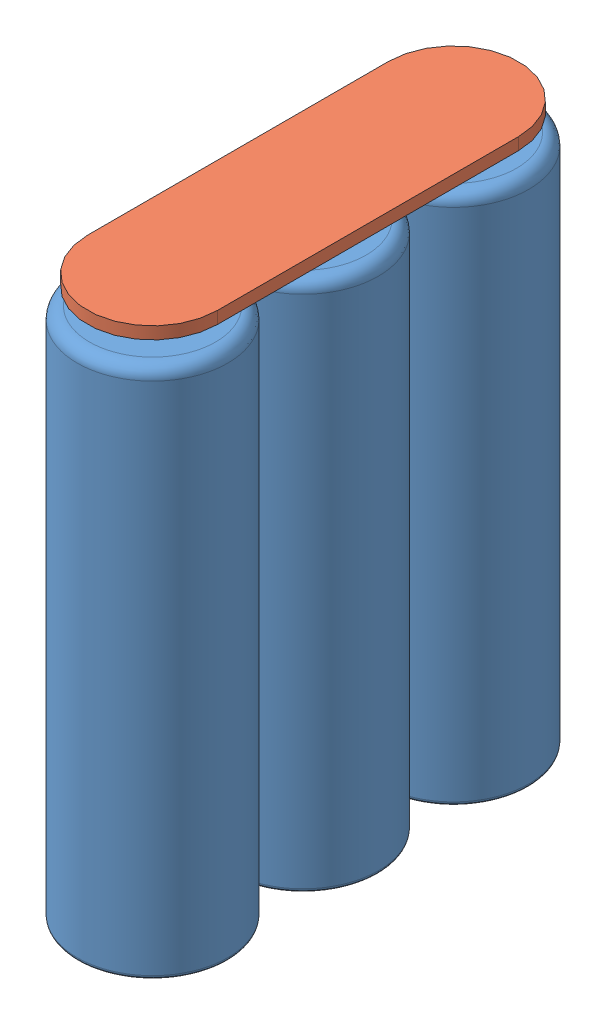
SolidWorks assembly battery_block, configuration По умолчанию. Lengths in mm.
Overall size (18.5 68.8 55.5).
4 component instances, 2 part files, 3 mates.
Components (placement in the parent):
- Sanjo NCR18650GA-1: Sanjo NCR18650GA [Standard] at origin size (18.5 65.3 18.5)
- Sanjo NCR18650GA-2: Sanjo NCR18650GA [Standard] at (0 0 18.5) size (18.5 65.3 18.5)
- Sanjo NCR18650GA-3: Sanjo NCR18650GA [Standard] at (0 0 37) size (18.5 65.3 18.5)
- balansir_pcb-1: balansir_pcb [По умолчанию] at (0 68.8 18.5) x (1 0 0) z (0 -1 0) size (16 53 1.5)
Mates (geometry in assembly coordinates):
- Concentric1: concentric anti-aligned: cylinder of Sanjo NCR18650GA-1 through (0 65.3 0) axis (0 -1 0) radius 9.25; cylinder of balansir_pcb-1 through (0 65.8 0) axis (0 1 0) radius 8
- Concentric2: concentric anti-aligned: cylinder of Sanjo NCR18650GA-3 through (0 65.3 37) axis (0 -1 0) radius 9.25; cylinder of balansir_pcb-1 through (0 65.8 37) axis (0 1 0) radius 8
- Distance1: distance = 2 mm anti-aligned: plane of balansir_pcb-1 through (0 67.3 37) normal (0 -1 0); plane of Sanjo NCR18650GA-1 through (0 65.3 0) normal (0 1 0)
